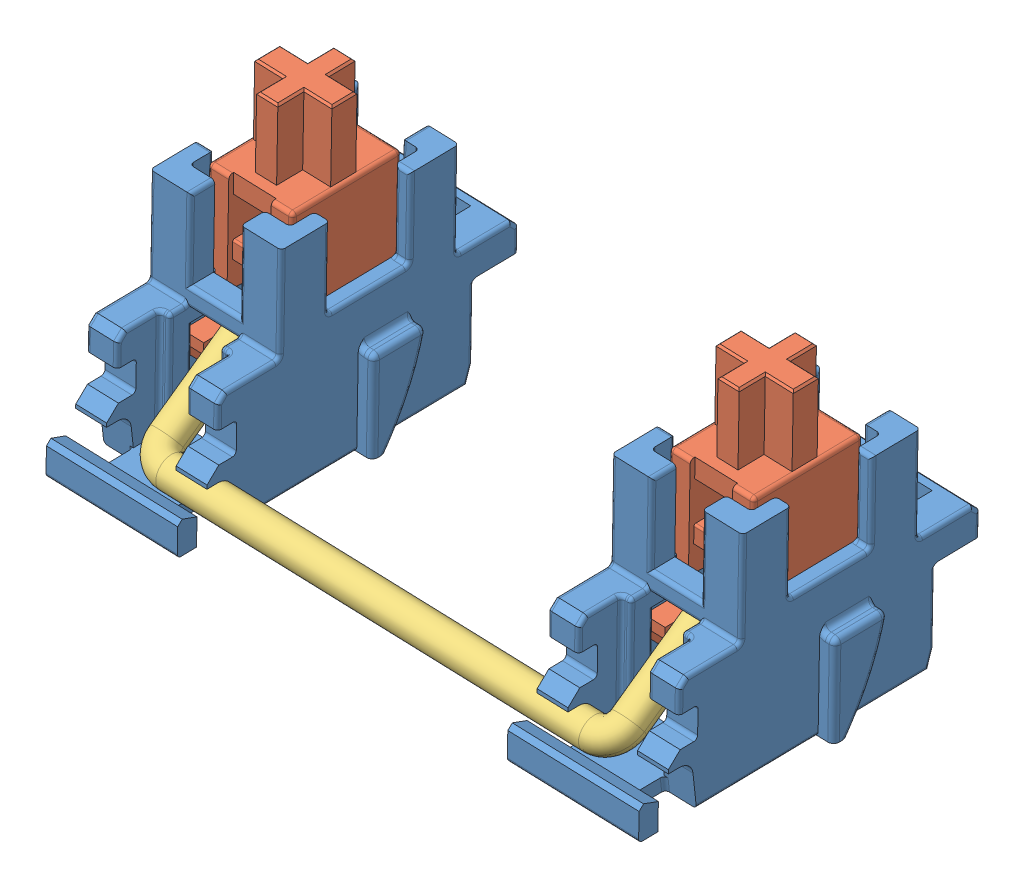
SolidWorks assembly as_stabil_asm, configuration Default. Lengths in mm.
Overall size (35.88 40.05 24.41).
6 component instances, 3 part files, 0 mates.
Components (placement in the parent):
- AS_TEST_STABIL_ASM-1: AS_TEST_STABIL_ASM [Default] at (-16.0428 -21.2219 8.4585) x (0.999391 -0.034894 -0.000609) z (0.034899 0.999239 0.017442) size (34.56 23.73 38.46)
  - STABIL_DOWN_MX-1: STABIL_DOWN_MX [Default] at (4.2 9.8 23.0591) size (8.52 17.6 11.65)
  - STABIL_MX-1: STABIL_MX [Default] at (2 12.625 23.7591) x (0 -1 0) z (-1 0 0) size (8.3 11.95 4.4)
  - STABIL_DOWN_MX-2: STABIL_DOWN_MX [Default] at (28.1 9.8 23.0591) size (8.52 17.6 11.65)
  - STABIL_MX-2: STABIL_MX [Default] at (25.9 12.625 23.7591) x (0 -1 0) z (-1 0 0) size (8.3 11.95 4.4)
  - MX_METAL-1: MX_METAL [Default] at (16.15 11.2814 26.5599) x (1 0 0) z (0 0.587785 -0.809017) size (25.52 12.2 1.68)
